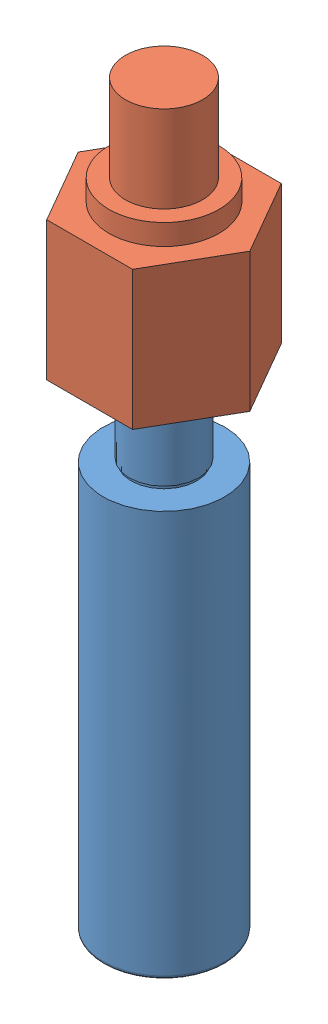
SolidWorks assembly Cup Punch and Chuck, configuration Default. Lengths in mm.
Overall size (49.5 213 42.87).
2 component instances, 2 part files, 1 mates.
Components (placement in the parent):
- Punch Body-1: Punch Body [Default] at (0 -71 0) size (35 142 35)
- Punch Chuck-1: Punch Chuck [Default] at (0 71 0) size (49.5 71 42.87)
Mates (geometry in assembly coordinates):
- Coincident1: coincident anti-aligned: plane of Punch Body-1 through (0 71 0) normal (0 1 0); plane of Punch Chuck-1 through (0 71 0) normal (0 -1 0)
